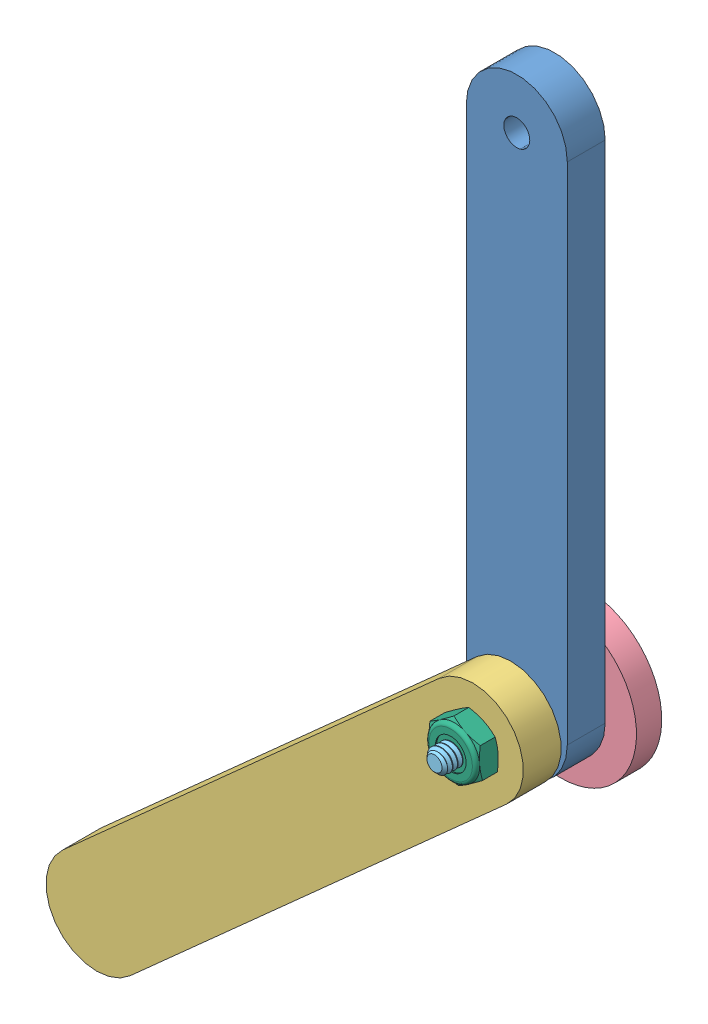
SolidWorks assembly pendulum, configuration Default. Lengths in mm.
Overall size (66.52 121.16 20.93).
7 component instances, 6 part files, 15 mates.
Components (placement in the parent):
- top_link-1: top_link [Default] at (6.35 0 4.7625) x (0 1 0) z (-1 0 0) size (76.2 4.76 12.7)
- FR144-ZZ-1: FR144-ZZ [Default] at (6.35 -63.5 2.0161) x (-0.923728 -0.383049 0) z (0 0 -1) size (7.52 7.52 2.78)
- bottom_link-1: bottom_link [Default] at (6.35 -63.5 10.287) x (0.74521 0.66683 0) z (-0.66683 0.74521 0) size (76.2 4.76 12.7)
- RC22-1: RC22 [Default] at (6.35 -63.5 -3.937) x (0.996967 -0.077826 0) z (-0.077826 -0.996967 0) size (19.05 3.17 19.05)
- FR144-ZZ-2: FR144-ZZ [Default] at (6.35 -63.5 2.7464) size (7.52 7.52 2.78)
- 4_40-75-91255A113-1: 4_40-75-91255A113 [91255A113] at (6.35 -63.5 -5.4356) x (-0.923728 -0.383049 0) z (0 0 -1) size (5.41 5.41 20.93)
- 4_40_THIN_LOCKNUT_90633A005-1: 4_40_THIN_LOCKNUT_90633A005 [90633A005] at (6.35 -63.5 10.287) x (0.56665 -0.823958 0) z (-0.823958 -0.56665 0) size (6.35 2.86 7.33)
Mates (geometry in assembly coordinates):
- Coincident1: coincident anti-aligned: plane of top_link-1 through (6.35 0 0) normal (0 0 -1); plane of assembly through (0 0 0) normal (0 0 1)
- Coincident2: coincident anti-aligned: plane of top_link-1 through (0 0 0) normal (-1 0 0); plane of assembly through (0 0 0) normal (1 0 0)
- Coincident4: coincident: line of top_link-1 through (12.7 0 0) axis (0 0 1); plane of assembly
- Coincident5: coincident anti-aligned: plane of top_link-1 through (6.35 0 0) normal (0 0 -1); plane of FR144-ZZ-1 through (6.35 -63.5 0) normal (0 0 1)
- Concentric1: concentric anti-aligned: cylinder of top_link-1 through (6.35 -63.5 4.7625) axis (0 0 -1) radius 3.1623; cylinder of FR144-ZZ-1 through (6.35 -63.5 0) axis (0 0 1) radius 1.5875
- Concentric2: concentric anti-aligned: cylinder of FR144-ZZ-1 through (6.35 -63.5 0) axis (0 0 1) radius 1.5875; cylinder of bottom_link-1 through (6.35 -63.5 5.5245) axis (0 0 -1) radius 1.632
- Concentric3: concentric aligned: cylinder of bottom_link-1 through (6.35 -63.5 5.5245) axis (0 0 -1) radius 1.632; cylinder of RC22-1 through (6.35 -63.5 -33.4542) axis (0 0 -1) radius 1.5875
- Concentric4: concentric aligned: cylinder of top_link-1 through (6.35 -63.5 4.7625) axis (0 0 -1) radius 3.1623; cylinder of FR144-ZZ-2 through (6.35 -63.5 4.7625) axis (0 0 -1) radius 1.5875
- Coincident8: coincident anti-aligned: plane of top_link-1 through (6.35 0 4.7625) normal (0 0 1); plane of FR144-ZZ-2 through (6.35 -63.5 4.7625) normal (0 0 -1)
- Coincident9: coincident anti-aligned: plane of RC22-1 through (6.35 -63.5 -36.6292) normal (0 0 -1); plane of 4_40-75-91255A113-1 through (7.3862 -65.9988 -36.6292) normal (0 0 1)
- Concentric5: concentric aligned: cylinder of RC22-1 through (6.35 -63.5 -33.4542) axis (0 0 -1) radius 1.5875; cylinder of 4_40-75-91255A113-1 through (6.35 -63.5 -38.1278) axis (0 0 -1) radius 2.7051
- Concentric6: concentric aligned: cylinder of FR144-ZZ-2 through (6.35 -63.5 5.5245) axis (0 0 -1) radius 3.7592; cylinder of 4_40_THIN_LOCKNUT_90633A005-1 through (6.35 -63.5 14.3351) axis (0 0 -1) radius 1.9297
- Coincident14: coincident anti-aligned: plane of bottom_link-1 through (6.35 -63.5 5.5245) normal (0 0 -1); plane of FR144-ZZ-2 through (6.35 -63.5 5.5245) normal (0 0 1)
- Coincident15: coincident anti-aligned: plane of bottom_link-1 through (6.35 -63.5 10.287) normal (0 0 1); plane of 4_40_THIN_LOCKNUT_90633A005-1 through (9.082 -57.7678 10.287) normal (0 0 -1)
- Coincident16: coincident anti-aligned: plane of FR144-ZZ-1 through (6.35 -63.5 -0.762) normal (0 0 -1); plane of RC22-1 through (6.35 -63.5 -0.762) normal (0 0 1)
